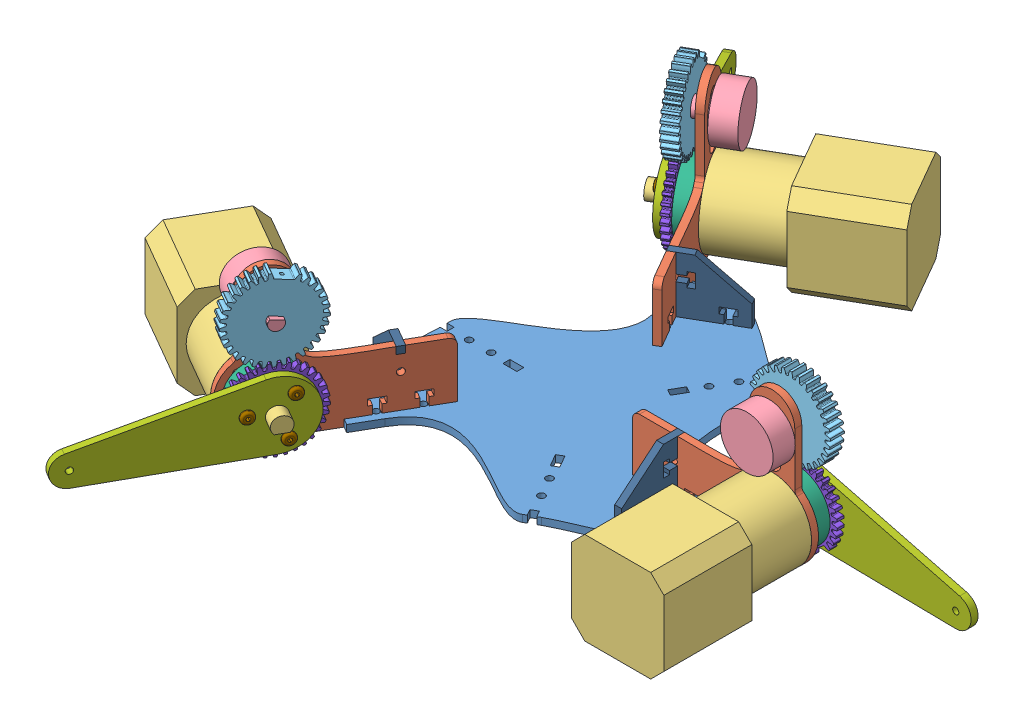
SolidWorks assembly robot_base, configuration Default. Lengths in mm.
Overall size (316.06 87.11 312.23).
37 component instances, 10 part files, 48 mates.
Components (placement in the parent):
- baseplate-1: baseplate [Default] at (-6.2424 -10.4202 4.8167) size (143.92 3.17 142.53)
- motor_plate-1: motor_plate [Default] at (95.6116 7.5795 20.7552) x (-1 0 0) z (0 0 -1) size (81.5 68.48 3.17)
- stepper-1: stepper [Default] at (95.6116 7.5795 90.9552) x (0 0 -1) z (-1 0 0) size (92.2 42 42)
- potentiometer2-1: potentiometer2 [Default] at (95.6111 42.9686 32.2552) x (0 0 -1) z (-0.02281 0.99974 0) size (26.5 24 24)
- gear_pot-1: gear_pot [Default] at (95.6111 42.9686 6.4052) x (-0.303545 0.952817 0) z (0 0 1) size (37.03 37 6.35)
- arm_upper_complete-1: arm_upper_complete [Default] at (88.6637 -5.6723 10.8016) x (0.795225 0.606314 0) z (0.606314 -0.795225 0) size (88.08 14.2 88.05) (flexible)
  - arm_collar-1: arm_collar [Default] at (13.5599 -1.2214 -6.3255) size (30.48 6.35 30.25)
  - arm_upper-1: arm_upper [Default] at (13.5599 -7.5714 -6.3255) x (-0.707107 0 -0.707107) z (0 1 0) size (92.08 30.48 3.17)
  - gear_stepper-1: gear_stepper [Default] at (13.5599 -4.3964 -6.3255) x (-0.959493 0 0.281733) z (0 1 0) size (37.03 37 3.17)
  - 4-40_12_screw-1: 4-40_12_screw [Default] at (4.761 5.1286 -1.2455) x (0.825951 0 0.563741) z (0.563741 0 -0.825951) size (5.41 14.2 5.41)
  - 4-40_12_screw-2: 4-40_12_screw [Default] at (22.3587 5.1286 -1.2455) x (0.604288 0 0.796766) z (0.796766 0 -0.604288) size (5.41 14.2 5.41)
  - 4-40_12_screw-3: 4-40_12_screw [Default] at (13.5599 5.1286 -16.4855) x (-0.60826 0 0.793738) z (0.793738 0 0.60826) size (5.41 14.2 5.41)
- motor_plate_support-1: motor_plate_support [Default] at (49.4471 6.4708 20.7552) x (0 0 -1) z (1 0 0) size (28.57 28.57 3.17)
- arm_upper_complete-4: arm_upper_complete [Default] at (-48.1298 -6.4819 -82.7041) x (-0.353553 0.707107 -0.612372) z (-0.353553 -0.707107 -0.612372) size (88.08 14.2 88.05) (flexible)
  - arm_collar-1: arm_collar [Default] at (13.5599 -1.2214 -6.3255) size (30.48 6.35 30.25)
  - arm_upper-1: arm_upper [Default] at (13.5599 -7.5714 -6.3255) x (-0.707107 0 -0.707107) z (0 1 0) size (92.08 30.48 3.17)
  - gear_stepper-1: gear_stepper [Default] at (13.5599 -4.3964 -6.3255) x (-0.959493 0 0.281733) z (0 1 0) size (37.03 37 3.17)
  - 4-40_12_screw-1: 4-40_12_screw [Default] at (4.761 5.1286 -1.2455) x (0.952213 0 0.305436) z (0.305436 0 -0.952213) size (5.41 14.2 5.41)
  - 4-40_12_screw-2: 4-40_12_screw [Default] at (22.3587 5.1286 -1.2455) x (0.806013 0 0.591898) z (0.591898 0 -0.806013) size (5.41 14.2 5.41)
  - 4-40_12_screw-3: 4-40_12_screw [Default] at (13.5599 5.1286 -16.4855) x (-0.35728 0 0.933997) z (0.933997 0 0.35728) size (5.41 14.2 5.41)
- arm_upper_complete-5: arm_upper_complete [Default] at (-60.2082 -5.7041 83.3183) x (-0.396211 0.609973 0.686257) z (-0.304987 -0.792422 0.528252) size (88.08 14.2 88.05) (flexible)
  - arm_collar-1: arm_collar [Default] at (13.5599 -1.2214 -6.3255) size (30.48 6.35 30.25)
  - arm_upper-1: arm_upper [Default] at (13.5599 -7.5714 -6.3255) x (-0.707107 0 -0.707107) z (0 1 0) size (92.08 30.48 3.17)
  - gear_stepper-1: gear_stepper [Default] at (13.5599 -4.3964 -6.3255) x (-0.959493 0 0.281733) z (0 1 0) size (37.03 37 3.17)
  - 4-40_12_screw-1: 4-40_12_screw [Default] at (4.761 5.1286 -1.2455) x (0.645771 0 0.763531) z (0.763531 0 -0.645771) size (5.41 14.2 5.41)
  - 4-40_12_screw-2: 4-40_12_screw [Default] at (22.3587 5.1286 -1.2455) x (0.370008 0 0.929029) z (0.929029 0 -0.370008) size (5.41 14.2 5.41)
  - 4-40_12_screw-3: 4-40_12_screw [Default] at (13.5599 5.1286 -16.4855) x (-0.797851 0 0.602855) z (0.602855 0 0.797851) size (5.41 14.2 5.41)
- stepper-4: stepper [Default] at (-131.7676 7.5795 49.9556) x (0.866025 0 0.5) z (0.5 0 -0.866025) size (92.2 42 42)
- stepper-5: stepper [Default] at (17.4285 7.5792 -126.461) x (-0.866025 0 0.5) z (0.5 0 0.866025) size (92.2 42 42)
- motor_plate-4: motor_plate [Default] at (-70.9726 7.5795 85.0556) x (0.5 0 -0.866025) z (0.866025 0 0.5) size (81.5 68.48 3.17)
- motor_plate-5: motor_plate [Default] at (-43.3663 7.5795 -91.3607) x (0.5 0 0.866025) z (-0.866025 0 0.5) size (81.5 68.48 3.17)
- motor_plate_support-4: motor_plate_support [Default] at (-47.8903 6.4708 45.076) x (0.866025 0 0.5) z (-0.5 0 0.866025) size (28.57 28.57 3.17)
- motor_plate_support-5: motor_plate_support [Default] at (-20.2841 6.4708 -51.3811) x (-0.866025 0 0.5) z (-0.5 0 -0.866025) size (28.57 28.57 3.17)
- potentiometer2-6: potentiometer2 [Default] at (-80.9316 43.0542 79.3052) x (0.866025 0 0.5) z (-0.489802 0.200934 0.848363) size (26.5 24 24)
- potentiometer2-7: potentiometer2 [Default] at (-33.4068 43.0538 -97.1103) x (-0.866025 0 0.5) z (-0.387537 -0.631871 -0.671234) size (26.5 24 24)
- gear_pot-6: gear_pot [Default] at (-48.9952 43.0538 -88.1103) x (0.28283 0.824639 0.489875) z (-0.866025 0 0.5) size (37.03 37 6.35)
- gear_pot-7: gear_pot [Default] at (-65.3432 43.0542 88.3052) x (0.498267 0.083192 -0.863023) z (0.866025 0 0.5) size (37.03 37 6.35)
Mates (geometry in assembly coordinates):
- Coincident1: coincident anti-aligned: plane of baseplate-1 through (32.8885 -7.2452 -14.6839) normal (0 1 0); plane of motor_plate-1 through (57.3846 -7.2452 17.5802) normal (0 -1 0)
- Coincident2: coincident anti-aligned: plane of baseplate-1 through (66.7826 -7.2452 17.5802) normal (1 0 0); plane of motor_plate-1 through (66.7826 -10.4202 17.5802) normal (-1 0 0)
- Coincident3: coincident anti-aligned: plane of baseplate-1 through (32.1116 -7.2452 20.7552) normal (0 0 -1); plane of motor_plate-1 through (69.6011 18.1034 20.7552) normal (0 0 1)
- Coincident4: coincident anti-aligned: plane of motor_plate-1 through (69.6011 18.1034 20.7552) normal (0 0 1); plane of stepper-1 through (95.6116 7.5795 20.7552) normal (0 0 -1)
- Concentric1: concentric aligned: cylinder of motor_plate-1 through (95.6116 7.5795 17.5802) axis (0 0 1) radius 11.049; cylinder of stepper-1 through (95.6116 7.5795 18.7552) axis (0 0 1) radius 11
- Concentric7: concentric aligned: cylinder of motor_plate-1 through (105.5114 17.4793 17.5802) axis (0 0 1) radius 1.6; cylinder of stepper-1 through (105.511 17.479 20.7552) axis (0 0 1) radius 1.5
- Tangent1: tangent anti-aligned: plane of motor_plate-1 through (91.6111 47.7056 17.5802) normal (1 0 0); cylinder of potentiometer2-1 through (95.6111 42.9686 32.2552) axis (0 0 1) radius 4
- Coincident5: coincident anti-aligned: plane of motor_plate-1 through (69.6011 18.1034 20.7552) normal (0 0 1); plane of potentiometer2-1 through (91.6121 42.8773 20.7552) normal (0 0 -1)
- Concentric8: concentric anti-aligned: cylinder of potentiometer2-1 through (95.6111 42.9686 32.2552) axis (0 0 1) radius 3; cylinder of gear_pot-1 through (95.6111 42.9686 12.7552) axis (0 0 -1) radius 3
- Coincident6: coincident anti-aligned: plane of potentiometer2-1 through (94.0522 45.5317 12.7552) normal (-0.99974 -0.02281 0); plane of gear_pot-1 through (94.1707 40.3369 12.7552) normal (0.99974 0.02281 0)
- Coincident7: coincident anti-aligned: plane of potentiometer2-1 through (95.6111 42.9686 12.7552) normal (0 0 -1); plane of gear_pot-1 through (77.9614 37.9306 12.7552) normal (0 0 1)
- Concentric10: concentric anti-aligned: cylinder of stepper-1 through (95.6116 7.5795 -1.2448) axis (0 0 1) radius 4; cylinder of arm_upper_complete-1/arm_collar-1 through (95.6116 7.5795 15.9302) axis (0 0 -1) radius 4
- Coincident11: coincident aligned: plane of gear_pot-1 through (77.9614 37.9306 6.4052) normal (0 0 -1); plane of arm_upper_complete-1/gear_stepper-1 through (110.0648 -3.734 6.4052) normal (0 0 -1)
- Coincident12: coincident anti-aligned: plane of baseplate-1 through (49.4471 -7.2452 27.1052) normal (0 0 -1); plane of motor_plate_support-1 through (52.6221 -10.4202 27.1052) normal (0 0 1)
- Coincident13: coincident anti-aligned: plane of baseplate-1 through (32.8885 -7.2452 -14.6839) normal (0 1 0); plane of motor_plate_support-1 through (52.6221 -7.2452 27.1052) normal (0 -1 0)
- Coincident14: coincident anti-aligned: plane of baseplate-1 through (49.4471 -7.2452 20.7552) normal (1 0 0); plane of motor_plate_support-1 through (49.4471 26.0923 17.5802) normal (-1 0 0)
- Coincident15: coincident anti-aligned: plane of baseplate-1 through (-14.3659 -7.2452 -34.7806) normal (0.866025 0 -0.5); plane of motor_plate-5 through (-33.1107 18.1034 -67.2475) normal (-0.866025 0 0.5)
- Coincident16: coincident anti-aligned: plane of baseplate-1 through (-14.3659 -7.2452 -34.7806) normal (-0.5 0 -0.866025); plane of motor_plate-5 through (-14.3659 -10.4202 -34.7806) normal (0.5 0 0.866025)
- Coincident17: coincident aligned: plane of baseplate-1 through (32.8885 -10.4202 -14.6839) normal (0 -1 0); plane of motor_plate-5 through (-17.5409 -10.4202 -40.2798) normal (0 -1 0)
- Concentric11: concentric aligned: cylinder of stepper-5 through (-45.0985 7.5792 -90.361) axis (0.866025 0 -0.5) radius 11; cylinder of motor_plate-5 through (-46.1159 7.5795 -89.7732) axis (0.866025 0 -0.5) radius 11.049
- Concentric12: concentric aligned: cylinder of stepper-5 through (-48.3162 -2.3203 -99.9342) axis (0.866025 0 -0.5) radius 1.5; cylinder of motor_plate-5 through (-51.0659 -2.3203 -98.3467) axis (0.866025 0 -0.5) radius 1.6
- Coincident18: coincident anti-aligned: plane of stepper-5 through (-43.3665 7.5792 -91.361) normal (-0.866025 0 0.5); plane of motor_plate-5 through (-30.3611 18.1034 -68.835) normal (0.866025 0 -0.5)
- Concentric13: concentric anti-aligned: cylinder of arm_upper_complete-4/arm_upper-1 through (-54.4949 7.5792 -84.936) axis (-0.866025 0 0.5) radius 4; cylinder of stepper-5 through (-62.419 7.5792 -80.361) axis (0.866025 0 -0.5) radius 4
- Tangent2: tangent anti-aligned: plane of motor_plate-5 through (-44.1157 47.7056 -86.3087) normal (-0.5 0 -0.866025); cylinder of potentiometer2-7 through (-33.4068 43.0538 -97.1103) axis (0.866025 0 -0.5) radius 4
- Coincident19: coincident anti-aligned: plane of motor_plate-5 through (-30.3611 18.1034 -68.835) normal (0.866025 0 -0.5); plane of potentiometer2-7 through (-44.6298 46.1541 -93.5491) normal (-0.866025 0 0.5)
- Coincident20: coincident anti-aligned: plane of potentiometer2-7 through (-51.775 42.5747 -89.925) normal (-0.315935 0.775074 -0.547216); plane of gear_pot-6 through (-55.9752 42.5747 -87.5) normal (0.315935 -0.775074 0.547216)
- Concentric15: concentric aligned: cylinder of potentiometer2-7 through (-33.4068 43.0538 -97.1103) axis (0.866025 0 -0.5) radius 3; cylinder of gear_pot-6 through (-54.4945 43.0538 -84.9353) axis (0.866025 0 -0.5) radius 3
- Coincident21: coincident anti-aligned: plane of potentiometer2-7 through (-49.943 45.379 -89.7519) normal (-0.866025 0 0.5); plane of gear_pot-6 through (-56.4021 53.891 -100.9393) normal (0.866025 0 -0.5)
- Coincident22: coincident aligned: plane of arm_upper_complete-4/gear_stepper-1 through (-62.4124 -1.7023 -98.6495) normal (-0.866025 0 0.5); plane of gear_pot-6 through (-61.9014 53.891 -97.7643) normal (-0.866025 0 0.5)
- Coincident25: coincident anti-aligned: plane of baseplate-1 through (-20.2841 -7.2452 -51.3811) normal (0.866025 0 -0.5); plane of motor_plate_support-5 through (-21.8716 6.4708 -54.1307) normal (-0.866025 0 0.5)
- Coincident26: coincident anti-aligned: plane of baseplate-1 through (-20.2841 -7.2452 -51.3811) normal (-0.5 0 -0.866025); plane of motor_plate_support-5 through (-23.0337 26.0923 -49.7936) normal (0.5 0 0.866025)
- Coincident27: coincident anti-aligned: plane of baseplate-1 through (32.8885 -7.2452 -14.6839) normal (0 1 0); plane of motor_plate_support-5 through (-16.3723 -7.2452 -57.3057) normal (0 -1 0)
- Coincident28: coincident anti-aligned: plane of baseplate-1 through (32.8885 -7.2452 -14.6839) normal (0 1 0); plane of motor_plate-4 through (-49.1095 -7.2452 53.5376) normal (0 -1 0)
- Coincident29: coincident anti-aligned: plane of baseplate-1 through (-36.473 -7.2452 31.6505) normal (-0.866025 0 -0.5); plane of motor_plate-4 through (-55.2177 18.1034 64.1174) normal (0.866025 0 0.5)
- Coincident30: coincident anti-aligned: plane of baseplate-1 through (-36.473 -7.2452 31.6505) normal (-0.5 0 0.866025); plane of motor_plate-4 through (-36.473 -10.4202 31.6505) normal (0.5 0 -0.866025)
- Concentric16: concentric aligned: cylinder of stepper-4 through (-66.0228 -2.32 76.4824) axis (-0.866025 0 -0.5) radius 1.5; cylinder of motor_plate-4 through (-63.273 -2.3203 78.0696) axis (-0.866025 0 -0.5) radius 1.6
- Concentric17: concentric aligned: circle of stepper-4; circle of motor_plate-4
- Coincident31: coincident anti-aligned: plane of stepper-4 through (-70.9726 7.5795 85.0556) normal (0.866025 0 0.5); plane of motor_plate-4 through (-57.9674 18.1034 62.5299) normal (-0.866025 0 -0.5)
- Concentric18: concentric anti-aligned: cylinder of arm_upper_complete-5/arm_upper-1 through (-59.8442 7.5795 91.4806) axis (0.866025 0 0.5) radius 4; cylinder of stepper-4 through (-51.92 7.5795 96.0556) axis (-0.866025 0 -0.5) radius 4
- Coincident32: coincident anti-aligned: plane of motor_plate-4 through (-57.9674 18.1034 62.5299) normal (-0.866025 0 -0.5); plane of potentiometer2-6 through (-70.5705 46.9726 84.3591) normal (0.866025 0 0.5)
- Tangent3: tangent anti-aligned: plane of motor_plate-4 through (-66.2227 47.7056 83.1786) normal (-0.5 0 0.866025); cylinder of potentiometer2-6 through (-80.9316 43.0542 79.3052) axis (-0.866025 0 -0.5) radius 4
- Coincident34: coincident anti-aligned: plane of potentiometer2-6 through (-65.0418 45.993 87.7831) normal (0.866025 0 0.5); plane of gear_pot-7 through (-65.8286 61.3831 89.146) normal (-0.866025 0 -0.5)
- Coincident38: coincident anti-aligned: plane of potentiometer2-6 through (-65.166 45.0456 90.9983) normal (0.100467 0.979605 -0.174014); plane of gear_pot-7 through (-60.9658 45.0456 93.4233) normal (-0.100467 -0.979605 0.174014)
- Coincident40: coincident anti-aligned: line of potentiometer2-6 through (-62.6209 44.0015 86.59) axis (0.866025 0 0.5); line of gear_pot-7 through (-58.4207 44.0015 89.015) axis (-0.866025 0 -0.5)
- Coincident41: coincident aligned: plane of arm_upper_complete-5/gear_stepper-1 through (-67.0968 -3.6673 104.0425) normal (0.866025 0 0.5); plane of gear_pot-7 through (-60.3294 61.3831 92.321) normal (0.866025 0 0.5)
- Coincident42: coincident anti-aligned: plane of motor_plate-4 through (-57.9674 18.1034 62.5299) normal (-0.866025 0 -0.5); plane of motor_plate_support-4 through (-49.4778 6.4708 47.8256) normal (0.866025 0 0.5)
- Coincident43: coincident anti-aligned: plane of baseplate-1 through (32.8885 -7.2452 -14.6839) normal (0 1 0); plane of motor_plate_support-4 through (-65.9756 -7.2452 38.3006) normal (0 -1 0)
- Coincident44: coincident anti-aligned: plane of motor_plate-4 through (-45.1407 14.9798 46.6635) normal (-0.5 0 0.866025); plane of motor_plate_support-4 through (-45.1407 26.0923 46.6635) normal (0.5 0 -0.866025)
